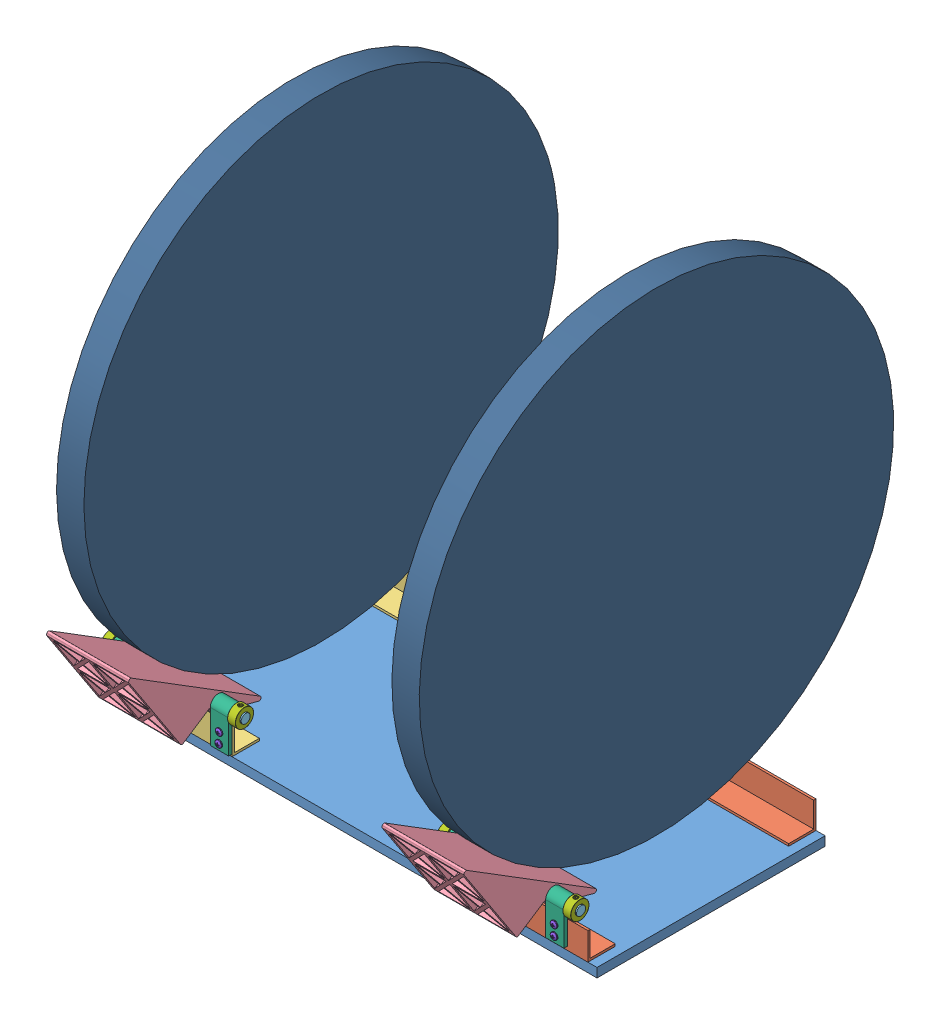
SolidWorks assembly RaisedMount, configuration Default. Lengths in mm.
Overall size (685.8 932.32 932.32).
37 component instances, 10 part files, 61 mates.
Components (placement in the parent):
- Board base-1: Board base [Default] at (-95.436 -57.183 853.5307) size (647.7 12.7 317.5)
- L-Bracket long-1: L-Bracket long [Default] at (140.2954 -29.0285 1013.2173) x (-1 0 0) z (0 0 -1) size (222.25 38.1 38.1)
- L-Bracket short-1: L-Bracket short [Default] at (-443.3458 -7.0948 695.7173) size (127 38.1 38.1)
- L-Bracket short-2: L-Bracket short [Default] at (-320.0378 -7.0948 1013.2173) x (-1 0 0) z (0 0 -1) size (127 38.1 38.1)
- L-Bracket long-2: L-Bracket long [Default] at (-8.3289 -29.0285 695.7173) size (222.25 38.1 38.1)
- ComponentAssembly-1: ComponentAssembly [Default] at (207.8673 -107.1883 962.8651) x (0 0 1) z (-1 0 0) size (186.6 216.09 190.5)
  - HingedWedge3DPrint-1: HingedWedge3DPrint [Default] at (169.27 200.7766 141.8841) x (0.54734 0.83691 0) z (0 0 1) size (196.37 94.54 114.3)
  - Shaft-1: Shaft [Default] at (43.9387 113.5053 46.6341) x (0.780539 0.625107 0) z (0 0 1) size (12.7 12.7 190.5)
  - AluminumPlate-1: AluminumPlate [Default] at (44.0657 113.5053 224.4341) x (0 -1 0) z (0 0 -1) size (56.97 22.1 25.4)
  - AluminumPlate-2: AluminumPlate [Default] at (44.0657 113.5053 84.7341) x (0 -1 0) z (0 0 -1) size (56.97 22.1 25.4)
  - 9946K150_SET SCREW SHAFT COLLAR-1: 9946K150_SET SCREW SHAFT COLLAR [9946K15] at (43.9387 113.5053 229.9903) x (0.473025 0.881049 0) z (0 0 1) size (25.4 25.4 11.11)
  - 9946K150_SET SCREW SHAFT COLLAR-2: 9946K150_SET SCREW SHAFT COLLAR [9946K15] at (43.9387 113.5053 53.7778) size (25.4 25.4 11.11)
- ComponentAssembly-2: ComponentAssembly [Default] at (-258.8577 -108.8393 962.8651) x (0 0 1) z (-1 0 0) size (186.6 216.09 190.5)
  - HingedWedge3DPrint-1: HingedWedge3DPrint [Default] at (169.27 200.7766 141.8841) x (0.54734 0.83691 0) z (0 0 1) size (196.37 94.54 114.3)
  - Shaft-1: Shaft [Default] at (43.9387 113.5053 46.6341) x (0.780539 0.625107 0) z (0 0 1) size (12.7 12.7 190.5)
  - AluminumPlate-1: AluminumPlate [Default] at (44.0657 113.5053 224.4341) x (0 -1 0) z (0 0 -1) size (56.97 22.1 25.4)
  - AluminumPlate-2: AluminumPlate [Default] at (44.0657 113.5053 84.7341) x (0 -1 0) z (0 0 -1) size (56.97 22.1 25.4)
  - 9946K150_SET SCREW SHAFT COLLAR-1: 9946K150_SET SCREW SHAFT COLLAR [9946K15] at (43.9387 113.5053 229.9903) x (0.473025 0.881049 0) z (0 0 1) size (25.4 25.4 11.11)
  - 9946K150_SET SCREW SHAFT COLLAR-2: 9946K150_SET SCREW SHAFT COLLAR [9946K15] at (43.9387 113.5053 53.7778) size (25.4 25.4 11.11)
- 91772A242_18-8 SS PAN HEAD PHILLIPS MACHINE SCREW-1: 91772A242_18-8 SS PAN HEAD PHILLIPS MACHINE SCREW [91772A242] at (135.8332 -16.7463 1005.2798) size (9.47 9.47 16.54)
- 91831A011_TYPE 18-8 STAINLESS STL NYLON-INSERT LOCKNUT-1: 91831A011_TYPE 18-8 STAINLESS STL NYLON-INSERT LOCKNUT [91831A011] at (135.8332 -16.7463 1010.0423) x (1 0 0) z (0 1 0) size (9.53 6.11 11)
- 91772A242_18-8 SS PAN HEAD PHILLIPS MACHINE SCREW-2: 91772A242_18-8 SS PAN HEAD PHILLIPS MACHINE SCREW [91772A242] at (135.8332 -30.7359 1005.2798) size (9.47 9.47 16.54)
- 91831A011_TYPE 18-8 STAINLESS STL NYLON-INSERT LOCKNUT-2: 91831A011_TYPE 18-8 STAINLESS STL NYLON-INSERT LOCKNUT [91831A011] at (135.8332 -30.7359 1010.0423) x (1 0 0) z (0 1 0) size (9.53 6.11 11)
- 91772A242_18-8 SS PAN HEAD PHILLIPS MACHINE SCREW-3: 91772A242_18-8 SS PAN HEAD PHILLIPS MACHINE SCREW [91772A242] at (-470.5918 -18.3973 1004.6717) size (9.47 9.47 16.54) (hidden)
- 91831A011_TYPE 18-8 STAINLESS STL NYLON-INSERT LOCKNUT-3: 91831A011_TYPE 18-8 STAINLESS STL NYLON-INSERT LOCKNUT [91831A011] at (-470.5918 -18.3973 1010.0423) x (1 0 0) z (0 1 0) size (9.53 6.11 11) (hidden)
- 91772A242_18-8 SS PAN HEAD PHILLIPS MACHINE SCREW-4: 91772A242_18-8 SS PAN HEAD PHILLIPS MACHINE SCREW [91772A242] at (-330.8918 -18.3973 1004.6717) size (9.47 9.47 16.54)
- 91831A011_TYPE 18-8 STAINLESS STL NYLON-INSERT LOCKNUT-4: 91831A011_TYPE 18-8 STAINLESS STL NYLON-INSERT LOCKNUT [91831A011] at (-330.8918 -18.3973 1010.0423) x (1 0 0) z (0 1 0) size (9.53 6.11 11)
- 91772A242_18-8 SS PAN HEAD PHILLIPS MACHINE SCREW-5: 91772A242_18-8 SS PAN HEAD PHILLIPS MACHINE SCREW [91772A242] at (-330.8918 -32.3869 1005.2798) size (9.47 9.47 16.54)
- 91831A011_TYPE 18-8 STAINLESS STL NYLON-INSERT LOCKNUT-5: 91831A011_TYPE 18-8 STAINLESS STL NYLON-INSERT LOCKNUT [91831A011] at (-330.8918 -32.3869 1010.0423) x (1 0 0) z (0 1 0) size (9.53 6.11 11)
- 91772A242_18-8 SS PAN HEAD PHILLIPS MACHINE SCREW-6: 91772A242_18-8 SS PAN HEAD PHILLIPS MACHINE SCREW [91772A242] at (-470.5918 -32.3869 1005.2798) x (0.999549 0.030029 0) z (0 0 1) size (9.47 9.47 16.54) (hidden)
- 91831A011_TYPE 18-8 STAINLESS STL NYLON-INSERT LOCKNUT-6: 91831A011_TYPE 18-8 STAINLESS STL NYLON-INSERT LOCKNUT [91831A011] at (-470.5918 -32.3869 1010.0423) x (1 0 0) z (0 1 0) size (9.53 6.11 11) (hidden)
- 91772A242_18-8 SS PAN HEAD PHILLIPS MACHINE SCREW-7: 91772A242_18-8 SS PAN HEAD PHILLIPS MACHINE SCREW [91772A242] at (-3.8668 -30.7359 1005.2798) size (9.47 9.47 16.54) (hidden)
- 91831A011_TYPE 18-8 STAINLESS STL NYLON-INSERT LOCKNUT-7: 91831A011_TYPE 18-8 STAINLESS STL NYLON-INSERT LOCKNUT [91831A011] at (-3.8668 -30.7359 1010.0423) x (1 0 0) z (0 1 0) size (9.53 6.11 11) (hidden)
- 91772A242_18-8 SS PAN HEAD PHILLIPS MACHINE SCREW-8: 91772A242_18-8 SS PAN HEAD PHILLIPS MACHINE SCREW [91772A242] at (-3.8668 -16.7463 1005.2798) size (9.47 9.47 16.54) (hidden)
- 91831A011_TYPE 18-8 STAINLESS STL NYLON-INSERT LOCKNUT-8: 91831A011_TYPE 18-8 STAINLESS STL NYLON-INSERT LOCKNUT [91831A011] at (-3.8668 -16.7463 1010.0423) x (1 0 0) z (0 1 0) size (9.53 6.11 11) (hidden)
- wheelchair wheel-1: wheelchair wheel [Default] at (46.9332 298.5024 825.687) x (0 -0.664214 -0.747542) z (1 0 0) size (660.4 660.4 38.1)
- wheelchair wheel-2: wheelchair wheel [Default] at (-419.7918 298.5024 825.687) x (0 0.239057 -0.971006) z (1 0 0) size (660.4 660.4 38.1)
Mates (geometry in assembly coordinates):
- Coincident1: coincident: plane of Board base-1 through (-95.436 -44.483 853.5307) normal (0 1 0); plane of L-Bracket long-2 through (-45.1418 -44.483 733.8173) normal (0 -1 0)
- Coincident3: coincident: plane of Board base-1 through (-95.436 -44.483 853.5307) normal (0 1 0); plane of L-Bracket short-2 through (-318.1918 -44.483 975.1173) normal (0 -1 0)
- Coincident4: coincident: plane of Board base-1 through (-95.436 -44.483 853.5307) normal (0 1 0); plane of L-Bracket short-1 through (-445.1918 -44.483 733.8173) normal (0 -1 0)
- Parallel2: parallel: line of Board base-1 through (-457.8918 -44.483 695.7173) axis (0 0 1); line of L-Bracket long-2 through (177.1082 -41.308 698.8923) axis (0 0 1)
- Coincident13: coincident: plane of Board base-1 through (-95.436 -44.483 853.5307) normal (0 1 0); plane of L-Bracket long-1 through (177.1082 -44.483 975.1173) normal (0 -1 0)
- Parallel6: parallel: plane of Board base-1 through (-457.8918 -44.483 1013.2173) normal (0 0 1); plane of L-Bracket short-2 through (-320.0378 -7.0948 1013.2173) normal (0 0 1)
- Parallel7: parallel: plane of L-Bracket short-1 through (-443.3458 -7.0948 695.7173) normal (0 0 -1); plane of Board base-1 through (-457.8918 -44.483 695.7173) normal (0 0 -1)
- Distance7: distance = 241.3 mm: line of L-Bracket short-2 through (-318.1918 -41.308 975.1173) axis (-1 0 0); line of L-Bracket short-1 through (-445.1918 -41.308 733.8173) axis (1 0 0)
- Coincident27: coincident: line of Board base-1 through (-457.8918 -44.483 1013.2173) axis (1 0 0); line of L-Bracket short-2 through (-318.1918 -44.483 1013.2173) axis (-1 0 0)
- Coincident28: coincident: line of Board base-1 through (-457.8918 -44.483 1013.2173) axis (1 0 0); line of L-Bracket long-1 through (177.1082 -44.483 1013.2173) axis (-1 0 0)
- Distance9: distance = 241.3 mm: line of L-Bracket long-2 through (-45.1418 -41.308 733.8173) axis (1 0 0); line of L-Bracket long-1 through (177.1082 -41.308 975.1173) axis (-1 0 0)
- Distance11: distance = 12.7 mm: plane of L-Bracket short-2 through (-445.1918 -6.383 975.1173) normal (-1 0 0); plane of Board base-1 through (-457.8918 -44.483 695.7173) normal (-1 0 0)
- Distance12: distance = 12.7 mm: plane of L-Bracket short-1 through (-445.1918 -6.383 733.8173) normal (-1 0 0); plane of Board base-1 through (-457.8918 -44.483 695.7173) normal (-1 0 0)
- Distance14: distance = 12.7 mm: plane of L-Bracket long-1 through (177.1082 -6.383 975.1173) normal (1 0 0); plane of Board base-1 through (189.8082 -44.483 695.7173) normal (1 0 0)
- Distance16: distance = 12.7 mm: plane of L-Bracket long-2 through (177.1082 -6.383 733.8173) normal (1 0 0); plane of Board base-1 through (189.8082 -44.483 695.7173) normal (1 0 0)
- Coincident29: coincident: plane of L-Bracket long-1 through (140.2954 -29.0285 1013.2173) normal (0 0 1); plane of ComponentAssembly-1/AluminumPlate-2 through (148.5332 6.317 1013.2173) normal (0 0 -1)
- Coincident30: coincident: plane of L-Bracket long-1 through (140.2954 -29.0285 1013.2173) normal (0 0 1); plane of ComponentAssembly-1/AluminumPlate-1 through (8.8332 6.317 1013.2173) normal (0 0 -1)
- Tangent2: tangent: plane of L-Bracket long-1 through (177.1082 -6.383 975.1173) normal (0 1 0); cylinder of ComponentAssembly-1/9946K150_SET SCREW SHAFT COLLAR-2 through (148.5332 6.317 1006.8038) axis (1 0 0) radius 12.7
- Coincident35: coincident: plane of L-Bracket short-2 through (-320.0378 -7.0948 1013.2173) normal (0 0 1); plane of ComponentAssembly-2/AluminumPlate-1 through (-457.8918 4.666 1013.2173) normal (0 0 -1)
- Coincident36: coincident: plane of L-Bracket short-2 through (-320.0378 -7.0948 1013.2173) normal (0 0 1); plane of ComponentAssembly-2/AluminumPlate-2 through (-318.1918 4.666 1013.2173) normal (0 0 -1)
- Coincident37: coincident: plane of L-Bracket short-2 through (-318.1918 -6.383 975.1173) normal (0 1 0); line of ComponentAssembly-2/AluminumPlate-1 through (-457.8918 -6.383 1006.9308) axis (-1 0 0)
- Coincident38: coincident: plane of L-Bracket short-2 through (-318.1918 -6.383 975.1173) normal (0 1 0); line of ComponentAssembly-2/AluminumPlate-2 through (-318.1918 -6.383 1006.9308) axis (-1 0 0)
- Coincident39: coincident: plane of L-Bracket short-2 through (-318.1918 -6.383 975.1173) normal (1 0 0); plane of ComponentAssembly-2/AluminumPlate-2 through (-318.1918 4.666 1006.9308) normal (1 0 0)
- Concentric1: concentric: circle of ComponentAssembly-1/AluminumPlate-2; circle of 91772A242_18-8 SS PAN HEAD PHILLIPS MACHINE SCREW-1
- Coincident40: coincident: plane of ComponentAssembly-1/AluminumPlate-2 through (148.5332 6.317 1017.9798) normal (0 0 1); circle of 91772A242_18-8 SS PAN HEAD PHILLIPS MACHINE SCREW-1
- Concentric2: concentric: circle of 91772A242_18-8 SS PAN HEAD PHILLIPS MACHINE SCREW-1; circle of 91831A011_TYPE 18-8 STAINLESS STL NYLON-INSERT LOCKNUT-1
- Coincident42: coincident: plane of L-Bracket long-1 through (140.2954 -29.0285 1010.0423) normal (0 0 -1); plane of 91831A011_TYPE 18-8 STAINLESS STL NYLON-INSERT LOCKNUT-1 through (131.0707 -24.9952 1010.0423) normal (0 0 1)
- Concentric5: concentric: circle of 91772A242_18-8 SS PAN HEAD PHILLIPS MACHINE SCREW-2; circle of 91831A011_TYPE 18-8 STAINLESS STL NYLON-INSERT LOCKNUT-2
- Concentric6: concentric: circle of ComponentAssembly-1/AluminumPlate-2; circle of 91831A011_TYPE 18-8 STAINLESS STL NYLON-INSERT LOCKNUT-2
- Coincident46: coincident: plane of ComponentAssembly-1/AluminumPlate-2 through (148.5332 6.317 1017.9798) normal (0 0 1); circle of 91772A242_18-8 SS PAN HEAD PHILLIPS MACHINE SCREW-2
- Coincident47: coincident: plane of L-Bracket long-1 through (140.2954 -29.0285 1010.0423) normal (0 0 -1); plane of 91831A011_TYPE 18-8 STAINLESS STL NYLON-INSERT LOCKNUT-2 through (131.0707 -38.9848 1010.0423) normal (0 0 1)
- Concentric7: concentric: circle of ComponentAssembly-2/AluminumPlate-1; circle of 91772A242_18-8 SS PAN HEAD PHILLIPS MACHINE SCREW-3
- Coincident48: coincident: plane of ComponentAssembly-2/AluminumPlate-1 through (-457.8918 4.666 1017.9798) normal (0 0 1); circle of 91772A242_18-8 SS PAN HEAD PHILLIPS MACHINE SCREW-3
- Concentric8: concentric: circle of 91772A242_18-8 SS PAN HEAD PHILLIPS MACHINE SCREW-3; circle of 91831A011_TYPE 18-8 STAINLESS STL NYLON-INSERT LOCKNUT-3
- Coincident49: coincident: plane of L-Bracket short-2 through (-320.0378 -7.0948 1010.0423) normal (0 0 -1); plane of 91831A011_TYPE 18-8 STAINLESS STL NYLON-INSERT LOCKNUT-3 through (-475.3543 -26.6462 1010.0423) normal (0 0 1)
- Concentric9: concentric: circle of 91772A242_18-8 SS PAN HEAD PHILLIPS MACHINE SCREW-4; circle of 91831A011_TYPE 18-8 STAINLESS STL NYLON-INSERT LOCKNUT-4
- Concentric10: concentric: circle of ComponentAssembly-2/AluminumPlate-2; circle of 91831A011_TYPE 18-8 STAINLESS STL NYLON-INSERT LOCKNUT-4
- Coincident50: coincident: plane of ComponentAssembly-2/AluminumPlate-2 through (-318.1918 4.666 1017.9798) normal (0 0 1); circle of 91772A242_18-8 SS PAN HEAD PHILLIPS MACHINE SCREW-4
- Coincident51: coincident: plane of L-Bracket short-2 through (-320.0378 -7.0948 1010.0423) normal (0 0 -1); plane of 91831A011_TYPE 18-8 STAINLESS STL NYLON-INSERT LOCKNUT-4 through (-335.6543 -26.6462 1010.0423) normal (0 0 1)
- Concentric11: concentric: circle of 91772A242_18-8 SS PAN HEAD PHILLIPS MACHINE SCREW-5; circle of 91831A011_TYPE 18-8 STAINLESS STL NYLON-INSERT LOCKNUT-5
- Concentric12: concentric: circle of ComponentAssembly-2/AluminumPlate-2; circle of 91831A011_TYPE 18-8 STAINLESS STL NYLON-INSERT LOCKNUT-5
- Coincident52: coincident: plane of ComponentAssembly-2/AluminumPlate-2 through (-318.1918 4.666 1017.9798) normal (0 0 1); plane of 91772A242_18-8 SS PAN HEAD PHILLIPS MACHINE SCREW-5 through (-330.8918 -32.3869 1017.9798) normal (0 0 -1)
- Coincident53: coincident: plane of L-Bracket short-2 through (-320.0378 -7.0948 1010.0423) normal (0 0 -1); plane of 91831A011_TYPE 18-8 STAINLESS STL NYLON-INSERT LOCKNUT-5 through (-335.6543 -40.6358 1010.0423) normal (0 0 1)
- Concentric13: concentric: circle of 91772A242_18-8 SS PAN HEAD PHILLIPS MACHINE SCREW-6; circle of 91831A011_TYPE 18-8 STAINLESS STL NYLON-INSERT LOCKNUT-6
- Concentric14: concentric: circle of ComponentAssembly-2/AluminumPlate-1; circle of 91831A011_TYPE 18-8 STAINLESS STL NYLON-INSERT LOCKNUT-6
- Coincident54: coincident: plane of L-Bracket short-2 through (-320.0378 -7.0948 1010.0423) normal (0 0 -1); plane of 91831A011_TYPE 18-8 STAINLESS STL NYLON-INSERT LOCKNUT-6 through (-475.3543 -40.6358 1010.0423) normal (0 0 1)
- Coincident55: coincident: plane of ComponentAssembly-2/AluminumPlate-1 through (-457.8918 4.666 1017.9798) normal (0 0 1); plane of 91772A242_18-8 SS PAN HEAD PHILLIPS MACHINE SCREW-6 through (-470.5918 -32.3869 1017.9798) normal (0 0 -1)
- Concentric15: concentric: circle of 91772A242_18-8 SS PAN HEAD PHILLIPS MACHINE SCREW-7; circle of 91831A011_TYPE 18-8 STAINLESS STL NYLON-INSERT LOCKNUT-7
- Coincident56: coincident: plane of L-Bracket long-1 through (140.2954 -29.0285 1010.0423) normal (0 0 -1); plane of 91831A011_TYPE 18-8 STAINLESS STL NYLON-INSERT LOCKNUT-7 through (-8.6293 -38.9848 1010.0423) normal (0 0 1)
- Concentric16: concentric: circle of ComponentAssembly-1/AluminumPlate-1; circle of 91831A011_TYPE 18-8 STAINLESS STL NYLON-INSERT LOCKNUT-7
- Coincident57: coincident: plane of ComponentAssembly-1/AluminumPlate-1 through (8.8332 6.317 1017.9798) normal (0 0 1); plane of 91772A242_18-8 SS PAN HEAD PHILLIPS MACHINE SCREW-7 through (-3.8668 -30.7359 1017.9798) normal (0 0 -1)
- Coincident58: coincident: plane of L-Bracket long-1 through (140.2954 -29.0285 1010.0423) normal (0 0 -1); plane of 91831A011_TYPE 18-8 STAINLESS STL NYLON-INSERT LOCKNUT-8 through (-8.6293 -24.9952 1010.0423) normal (0 0 1)
- Concentric17: concentric: circle of 91772A242_18-8 SS PAN HEAD PHILLIPS MACHINE SCREW-8; circle of 91831A011_TYPE 18-8 STAINLESS STL NYLON-INSERT LOCKNUT-8
- Concentric18: concentric: circle of ComponentAssembly-1/AluminumPlate-1; circle of 91831A011_TYPE 18-8 STAINLESS STL NYLON-INSERT LOCKNUT-8
- Coincident59: coincident: plane of ComponentAssembly-1/AluminumPlate-1 through (8.8332 6.317 1017.9798) normal (0 0 1); circle of 91772A242_18-8 SS PAN HEAD PHILLIPS MACHINE SCREW-8
- Width1: width: plane of L-Bracket long-1 through (-45.1418 -6.383 975.1173) normal (-1 0 0); plane of L-Bracket long-1 through (177.1082 -6.383 975.1173) normal (1 0 0); plane of ComponentAssembly-1/Shaft-1 through (-29.2668 6.317 1006.8038) normal (-1 0 0); plane of ComponentAssembly-1/Shaft-1 through (161.2332 6.317 1006.8038) normal (1 0 0)
- Width2: width: plane of ComponentAssembly-1/HingedWedge3DPrint-1 through (123.1332 93.5882 1132.1351) normal (1 0 0); plane of ComponentAssembly-1/HingedWedge3DPrint-1 through (8.8332 93.5882 1132.1351) normal (-1 0 0); plane of wheelchair wheel-1 through (85.0332 298.5024 825.687) normal (1 0 0); plane of wheelchair wheel-1 through (46.9332 298.5024 825.687) normal (-1 0 0)
- Tangent3: tangent: line of L-Bracket long-2 through (177.1082 -6.383 698.8923) axis (-1 0 0); cylinder of wheelchair wheel-1 through (85.0332 298.5024 825.687) axis (-1 0 0) radius 330.2
- Width3: width: plane of ComponentAssembly-2/HingedWedge3DPrint-1 through (-457.8918 91.9372 1132.1351) normal (-1 0 0); plane of ComponentAssembly-2/HingedWedge3DPrint-1 through (-343.5918 91.9372 1132.1351) normal (1 0 0); plane of wheelchair wheel-2 through (-381.6918 298.5024 825.687) normal (1 0 0); plane of wheelchair wheel-2 through (-419.7918 298.5024 825.687) normal (-1 0 0)
- Tangent4: tangent: cylinder of wheelchair wheel-2 through (-381.6918 298.5024 825.687) axis (-1 0 0) radius 330.2; line of L-Bracket short-1 through (-318.1918 -6.383 698.8923) axis (-1 0 0)
- Concentric19: concentric: circle of wheelchair wheel-1; circle of wheelchair wheel-2
